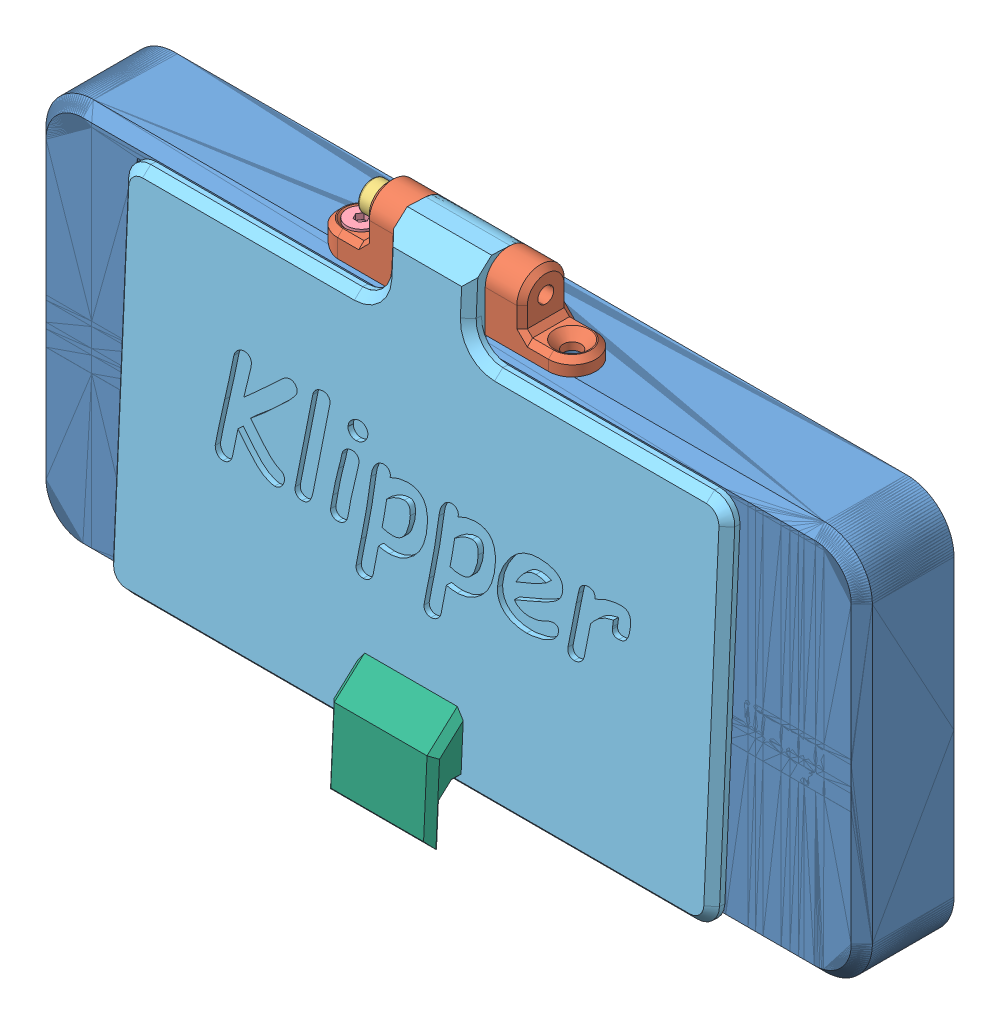
SolidWorks assembly 装配体, configuration 默认. Lengths in mm.
Overall size (156.81 90.78 29.55).
7 component instances, 6 part files, 12 mates.
Components (placement in the parent):
- 下壳-1: 下壳 [默认] at (-251.3248 -165.1515 39.45) size (156.81 73.9 17.5)
- 转轴座-1: 转轴座 [默认] at (-20.8248 38.2984 3.75) size (16.5 13.83 9)
- 转轴座-2: 转轴座 [默认] at (19.1752 38.2984 3.75) x (-1 0 0) z (0 0 -1) size (16.5 13.83 9)
- hexagon socket head cap screws gb-1: hexagon socket head cap screws gb [GB_FASTENER_SCREWS_HSHCS M3X12-N] at (-18.8248 46.1325 3.75) size (15 5.5 5.5)
- hexagon socket countersunk head screws gb-1: hexagon socket countersunk head screws gb [GB_FASTENER_SCREWS_HSCHS M3X8-N] at (-20.8248 41.3584 3.75) x (0 -1 0) z (-0.546944 0 0.837169) size (8 5.54 5.54)
- 屏幕盖子-1: 屏幕盖子 [默认] at (-0.8248 2.0368 10.8315) x (1 0 0) z (0 -0.998894 0.047027) size (115 12 83.38)
- 把手-1: 把手 [默认] at (-0.8248 -27.8125 14.7395) x (1 0 0) z (0 -0.998894 0.047027) size (20 5.5 20.5)
Mates (geometry in assembly coordinates):
- 同心1: concentric aligned: cylinder of 下壳-1 through (-20.8248 -35.6038 3.75) axis (0 1 0) radius 1.9; cylinder of 转轴座-1 through (-20.8248 41.2984 3.75) axis (0 1 0) radius 1.7
- 重合1: coincident anti-aligned: plane of 下壳-1 through (-251.3248 38.2984 39.45) normal (0 1 0); plane of 转轴座-1 through (-20.8248 38.2984 3.75) normal (0 -1 0)
- 平行1: parallel anti-aligned: line of 下壳-1 through (-68.2423 38.2984 -8.75) axis (1 0 0); line of 转轴座-1 through (-8.8248 38.2984 -0.75) axis (-1 0 0)
- 同心2: concentric anti-aligned: cylinder of 转轴座-1 through (-15.8248 46.1325 3.75) axis (1 0 0) radius 1.5; cylinder of hexagon socket head cap screws gb-1 through (-3.8248 46.1325 3.75) axis (-1 0 0) radius 1.5
- 重合3: coincident anti-aligned: plane of 转轴座-1 through (-15.8248 46.1325 3.75) normal (-1 0 0); plane of hexagon socket head cap screws gb-1 through (-15.8248 46.1325 3.75) normal (1 0 0)
- 同心4: concentric anti-aligned: cone of 转轴座-1 through (-20.8248 41.2984 3.75) axis (0 -1 0); cylinder of hexagon socket countersunk head screws gb-1 through (-20.8248 41.9455 3.75) axis (0 1 0) radius 1.5
- 重合5: coincident aligned: cone of 转轴座-1 through (-20.8248 41.2984 3.75) axis (0 -1 0); cone of hexagon socket countersunk head screws gb-1 through (-20.8248 39.4984 3.75) axis (0 -1 0)
- 重合8: coincident anti-aligned: plane of 转轴座-2 through (7.1752 41.2984 8.25) normal (-1 0 0); plane of 屏幕盖子-1 through (7.1752 45.4834 -10.0394) normal (1 0 0)
- 同心5: concentric anti-aligned: cylinder of hexagon socket head cap screws gb-1 through (-3.8248 46.1325 3.75) axis (-1 0 0) radius 1.5; cylinder of 屏幕盖子-1 through (-20.5402 46.1325 3.75) axis (1 0 0) radius 1.5
- 重合9: coincident anti-aligned: plane of 屏幕盖子-1 through (-0.8248 2.1543 13.3287) normal (0 0.047027 0.998894); plane of 把手-1 through (-0.8248 -27.8125 14.7395) normal (0 -0.047027 -0.998894)
- 同心6: concentric aligned: cylinder of 屏幕盖子-1 through (6.1752 -27.93 12.2423) axis (0 -0.047027 -0.998894) radius 1.7; cylinder of 把手-1 through (6.1752 -27.6714 17.7362) axis (0 -0.047027 -0.998894) radius 1.4
- 同心8: concentric aligned: cylinder of 屏幕盖子-1 through (-7.8248 -27.93 12.2423) axis (0 -0.047027 -0.998894) radius 1.7; cylinder of 把手-1 through (-7.8248 -27.6714 17.7362) axis (0 -0.047027 -0.998894) radius 1.4
